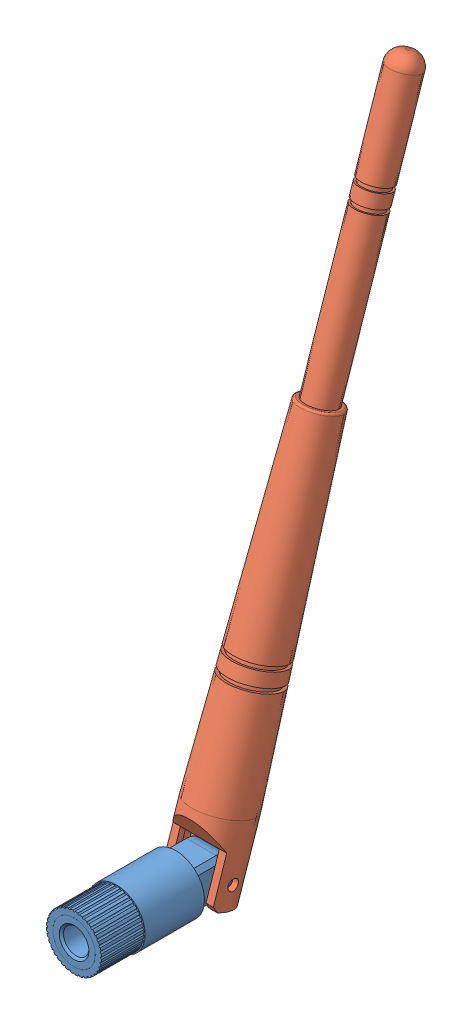
SolidWorks assembly BT_Antenna_Assem, configuration Default. Lengths in mm.
Overall size (14.01 152.32 85.29).
3 component instances, 2 part files, 0 mates.
Components (placement in the parent):
- BT_Antenna_Assem.stp-1: BT_Antenna_Assem.stp [Default] at origin size (14.01 152.32 85.29)
  - BT_Antenna1.stp-1: BT_Antenna1.stp [Default] at origin size (13.5 13.5 34)
  - BT_Antenna2.stp-1: BT_Antenna2.stp [Default] at (0.1 11.3735 -24.3268) x (-1 0 0) z (0 0.947789 -0.318898) size (14.01 14 156)
